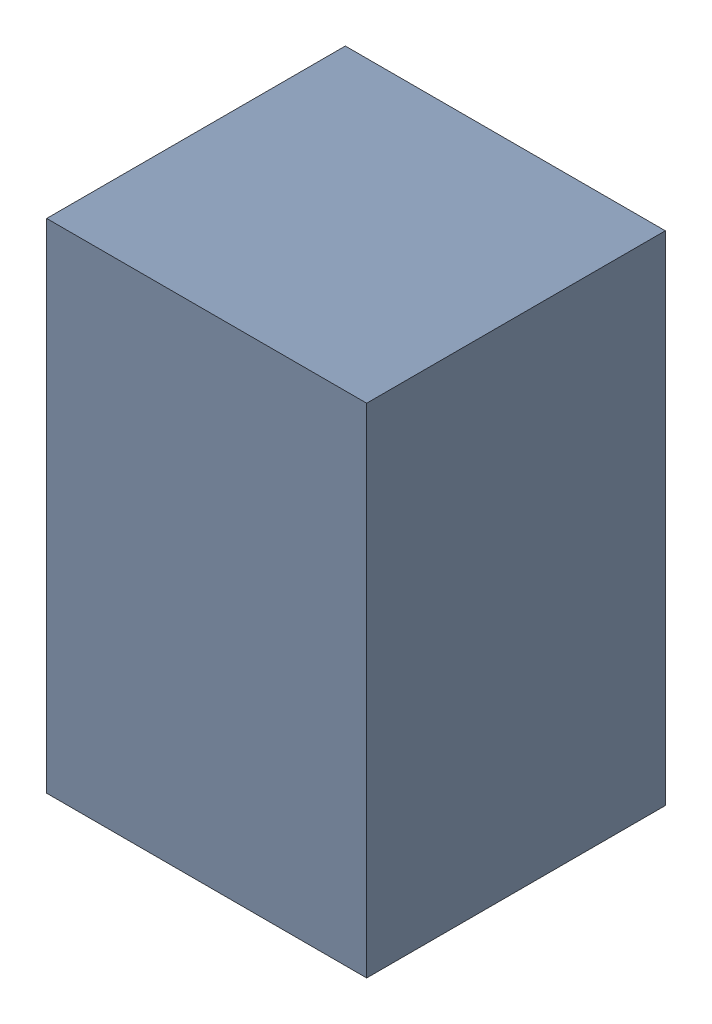
SolidWorks assembly C6, configuration Default. Lengths in mm.
Overall size (1.35 2.1 1.26).
2 component instances, 1 part files, 0 mates.
Components (placement in the parent):
- 407985696-1: 407985696 [Default] at (23.241 43.307 0.0127) size (1.35 2.1 1.26)
  - Extruded_1-1: Extruded_1 [Default] at origin size (1.35 2.1 1.26)
